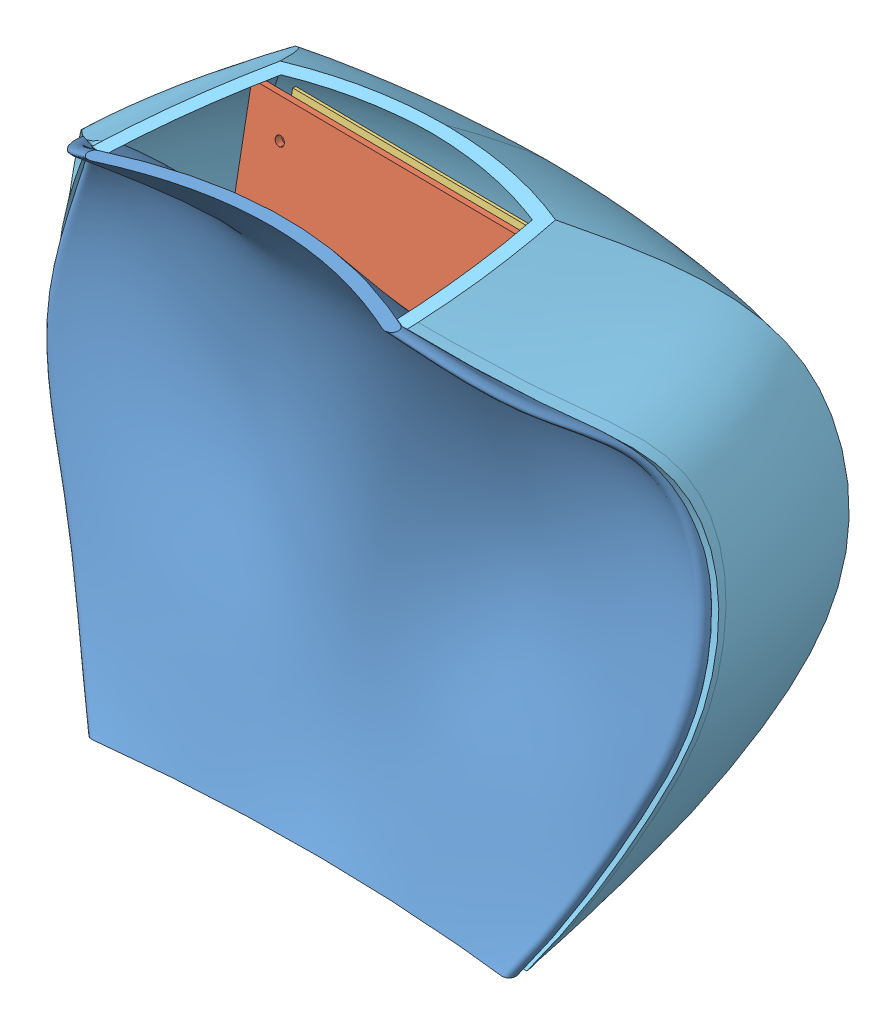
SolidWorks assembly Mochila, configuration Default. Lengths in mm.
Overall size (309.14 246.09 158.17).
9 component instances, 5 part files, 0 mates.
Components (placement in the parent):
- Molde-1: Molde [Default] at (366.0056 -91.1444 -34.3403) size (305.44 245.89 84.87)
- Jetson H-2: Jetson H [Default] at (432.8688 265.7526 -40.6786) x (-0.999962 0.00858 -0.00159) z (-0.008726 -0.98477 0.173641) size (180 45.5 180)
  - Base-1: Base [Default] at (67.0689 90.6709 139.4266) size (180 3 180)
  - Board-1: Board [Default] at (67.0689 104.6709 139.4266) size (170 31.5 170)
  - Separador-1: Separador [Default] at (-7.9311 93.6709 214.4266) x (0.99477 0 -0.102141) z (0.102141 0 0.99477) size (6 11 6)
  - Separador-2: Separador [Default] at (142.0689 93.6709 64.4266) size (6 11 6)
  - Separador-3: Separador [Default] at (142.0689 93.6709 214.4266) size (6 11 6)
  - Separador-4: Separador [Default] at (-7.9311 93.6709 64.4266) size (6 11 6)
- Cubierta-1: Cubierta [Default] at (365.8568 -91.3452 -34.2749) size (308.04 245.9 152.86)
